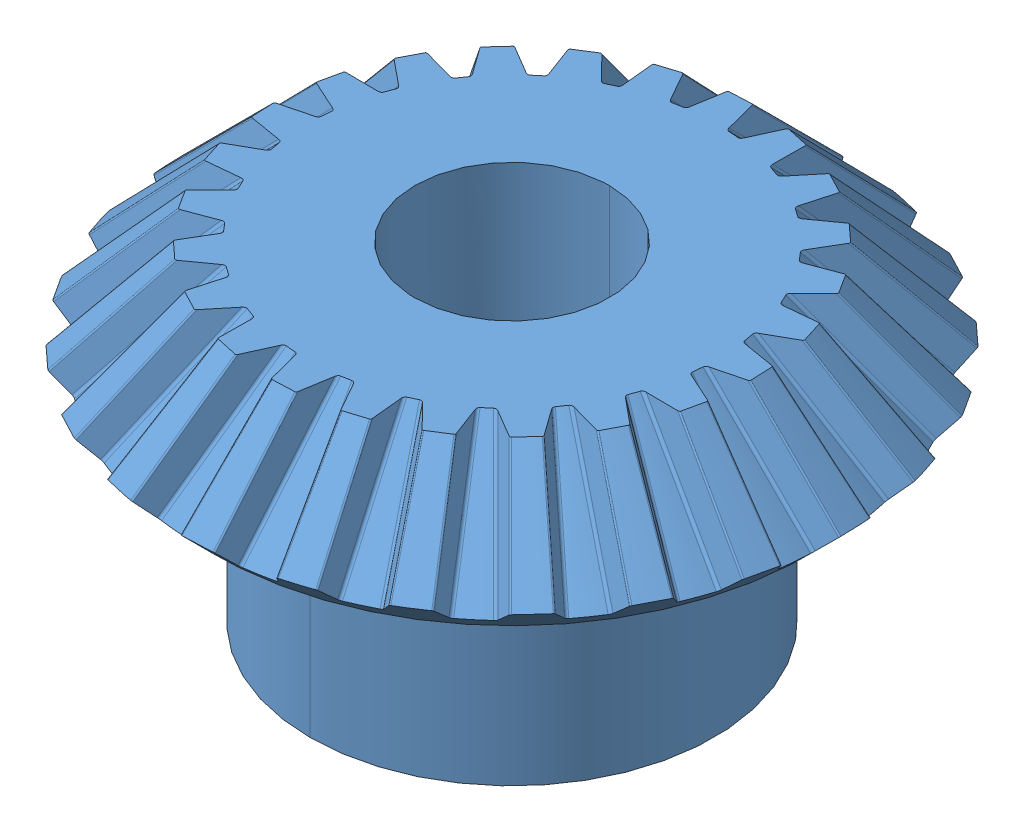
SolidWorks assembly 615406 Bevel Gear 24T Brass w, configuration Default. Lengths in mm.
Overall size (20.35 16.71 20.35).
2 component instances, 2 part files, 4 mates.
Components (placement in the parent):
- Copy of 615406 Bevel Gear 32DP 24T Brass^615406 Bevel Gear 24T Brass w-1: Copy of 615406 Bevel Gear 32DP 24T Brass^615406 Bevel Gear 24T Brass w [Default] at origin size (20.35 16.71 20.35) (virtual)
- Copy of 632134 91375A436 Set Screw 10-32 x 0.12Lg^615406 Bevel Gear 24T Brass w-1: Copy of 632134 91375A436 Set Screw 10-32 x 0.12Lg^615406 Bevel Gear 24T Brass w [Default] at (-4.8338 -1.7983 0) x (0 -1 0) z (-1 0 0) size (4.83 4.83 3.18) (virtual)
Mates (geometry in assembly coordinates):
- Coincident1: coincident: plane of Copy of 615406 Bevel Gear 32DP 24T Brass^615406 Bevel Gear 24T Brass w-1 through (0 0 0) normal (0 0 1); plane of Copy of 632134 91375A436 Set Screw 10-32 x 0.12Lg^615406 Bevel Gear 24T Brass w-1 through (-4.8338 -1.7983 0) normal (0 0 1)
- Distance1: distance = 4.8338 mm: plane of Copy of 632134 91375A436 Set Screw 10-32 x 0.12Lg^615406 Bevel Gear 24T Brass w-1 through (-4.8338 -1.7983 0) normal (-1 0 0); plane of Copy of 615406 Bevel Gear 32DP 24T Brass^615406 Bevel Gear 24T Brass w-1 through (0 0 0) normal (1 0 0)
- Distance2: distance = 1.7983 mm: plane of Copy of 615406 Bevel Gear 32DP 24T Brass^615406 Bevel Gear 24T Brass w-1 through (0 0 0) normal (0 1 0); plane of Copy of 632134 91375A436 Set Screw 10-32 x 0.12Lg^615406 Bevel Gear 24T Brass w-1 through (-4.8338 -1.7983 0) normal (0 -1 0)
- Coincident4: coordinate: point of Copy of 615406 Bevel Gear 32DP 24T Brass^615406 Bevel Gear 24T Brass w-1; point of assembly
